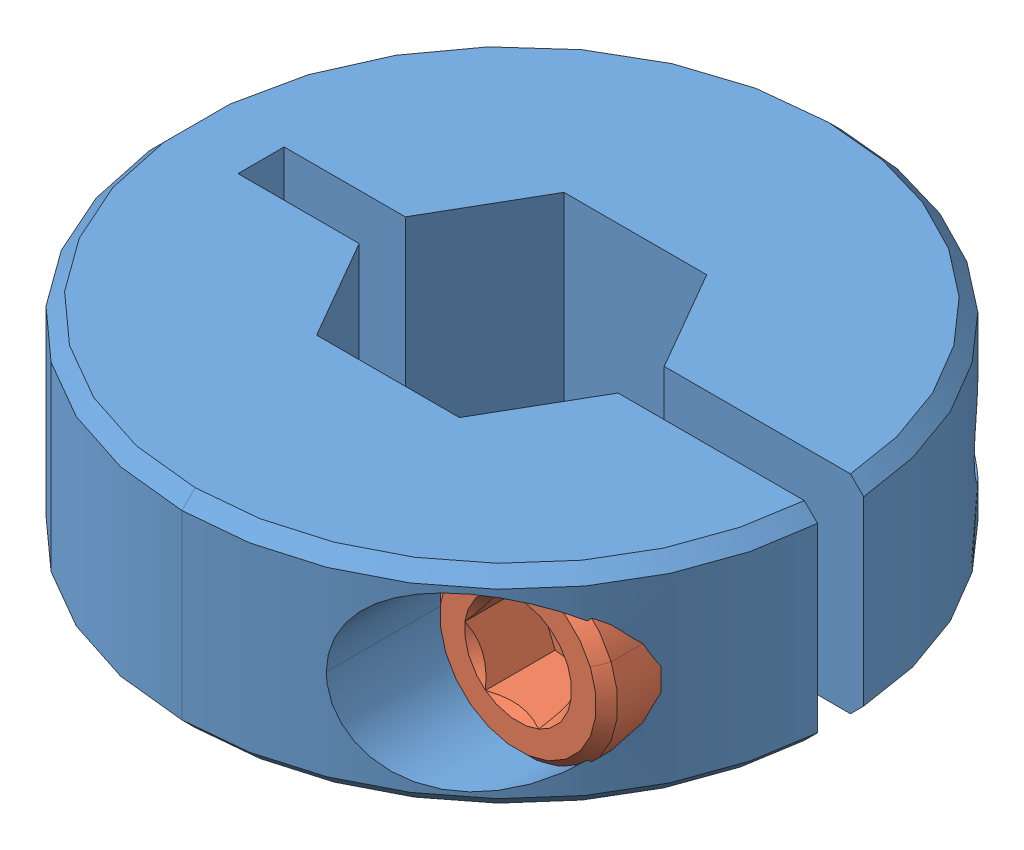
SolidWorks assembly Shaft Collar, configuration Default. Lengths in mm.
Overall size (25.37 8.96 25.4).
3 component instances, 2 part files, 0 mates.
Components (placement in the parent):
- Shaft Collar.STEP-1: Shaft Collar.STEP [Default] at origin size (25.37 8.96 25.4)
  - am-2300 Clamp Only.STEP-1: am-2300 Clamp Only.STEP [Default] at origin size (25.37 8 25.4)
  - am-2300 Screw Only_91251A192.STEP-1: am-2300 Screw Only_91251A192.STEP [Default] at (7.9698 4.0005 -5.969) x (-0.923728 -0.383049 0) z (0 0 -1) size (6.86 6.86 13.69)
